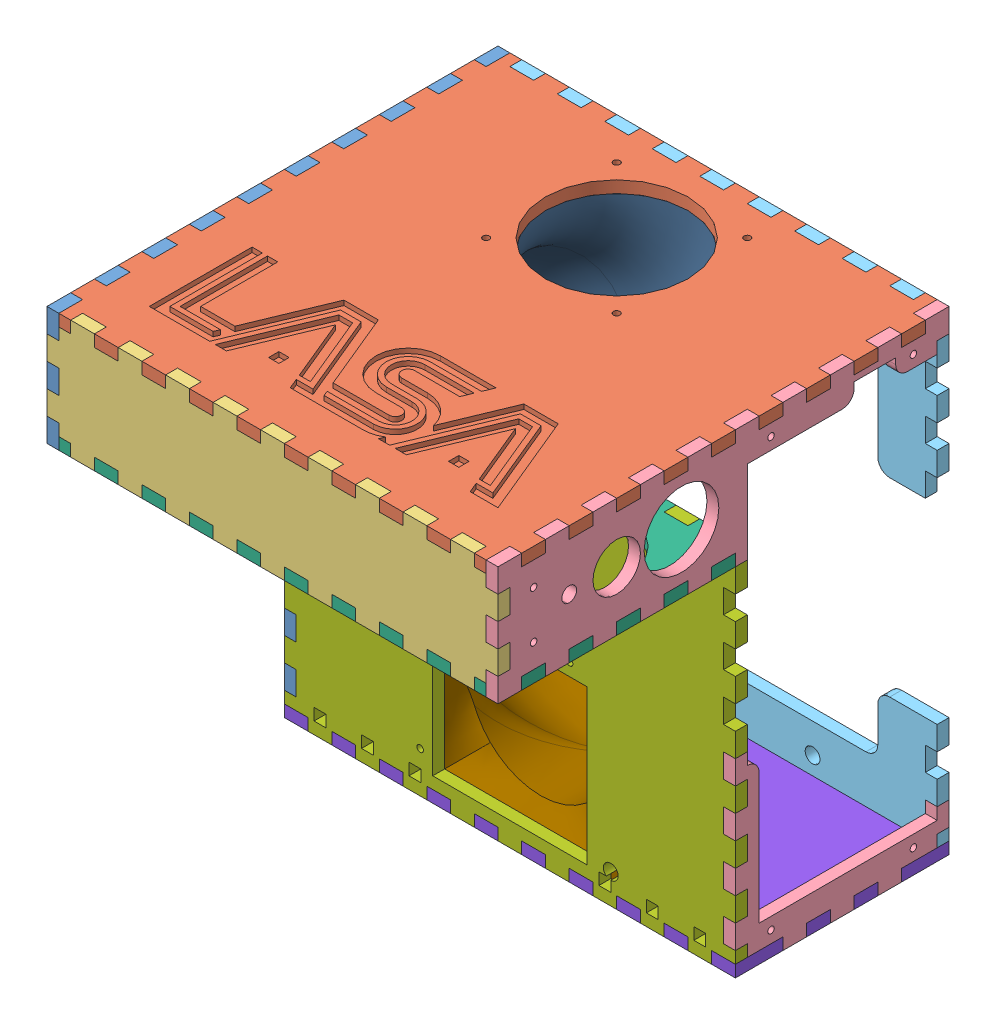
SolidWorks assembly Center Assembly, configuration Default. Lengths in mm.
Overall size (241.3 254 241.3).
10 component instances, 10 part files, 26 mates.
Components (placement in the parent):
- C Right Panel-1: C Right Panel [Default] at (96.1993 65.653 239.6839) size (6.35 254 241.3)
- C Top Panel-1: C Top Panel [Default] at (96.1993 313.303 366.6839) size (241.3 6.35 241.3)
- C Front Panel-1: C Front Panel [Default] at (96.1993 256.153 360.3339) size (241.3 63.5 6.35)
- C Left Panel-1: C Left Panel [Default] at (331.1493 65.653 239.6839) size (6.35 254 241.3)
- C Back Panel-2: C Back Panel [Default] at (96.1993 319.653 131.7339) x (1 0 0) z (0 1 0) size (241.3 6.35 254)
- C Inside Top-1: C Inside Top [Default] at (96.1993 256.153 366.6839) size (241.3 6.35 133.35)
- C Inside Back-1: C Inside Back [Default] at (96.1993 319.653 239.6839) x (1 0 0) z (0 1 0) size (241.3 6.35 196.85)
- C Bottom-1: C Bottom [Default] at (96.1993 65.653 239.6839) size (241.3 6.35 114.3)
- Ball Tube Part v2 A-1: Ball Tube Part v2 A [Default] at (261.2993 72.003 233.3339) size (177.68 162.89 99.66)
- Ball Tube Part v2 B-1: Ball Tube Part v2 B [Default] at (261.2993 200.9554 2.7815) x (1 0 0) z (0 -1 0) size (161.8 95.25 123.1)
Mates (geometry in assembly coordinates):
- Coincident1: coincident aligned: plane of C Right Panel-1 through (102.5493 319.653 366.6839) normal (0 1 0); plane of C Top Panel-1 through (96.1993 319.653 366.6839) normal (0 1 0)
- Coincident2: coincident aligned: plane of C Right Panel-1 through (96.1993 65.653 239.6839) normal (-1 0 0); plane of C Top Panel-1 through (96.1993 319.653 366.6839) normal (-1 0 0)
- Coincident3: coincident aligned: plane of C Right Panel-1 through (102.5493 256.153 366.6839) normal (0 0 1); plane of C Top Panel-1 through (96.1993 319.653 366.6839) normal (0 0 1)
- Coincident4: coincident aligned: plane of C Top Panel-1 through (96.1993 319.653 366.6839) normal (0 1 0); plane of C Front Panel-1 through (96.1993 319.653 366.6839) normal (0 1 0)
- Coincident5: coincident aligned: plane of C Right Panel-1 through (96.1993 65.653 239.6839) normal (-1 0 0); plane of C Front Panel-1 through (96.1993 256.153 366.6839) normal (-1 0 0)
- Coincident6: coincident aligned: plane of C Top Panel-1 through (96.1993 319.653 366.6839) normal (0 0 1); plane of C Front Panel-1 through (96.1993 256.153 366.6839) normal (0 0 1)
- Coincident7: coincident aligned: plane of C Front Panel-1 through (96.1993 256.153 366.6839) normal (0 0 1); plane of C Left Panel-1 through (337.4993 256.153 366.6839) normal (0 0 1)
- Coincident8: coincident aligned: plane of C Top Panel-1 through (96.1993 319.653 366.6839) normal (0 1 0); plane of C Left Panel-1 through (337.4993 319.653 366.6839) normal (0 1 0)
- Coincident9: coincident aligned: plane of C Top Panel-1 through (337.4993 319.653 366.6839) normal (1 0 0); plane of C Left Panel-1 through (337.4993 65.653 239.6839) normal (1 0 0)
- Coincident10: coincident aligned: plane of C Left Panel-1 through (337.4993 319.653 125.3839) normal (0 0 -1); plane of C Back Panel-2 through (96.1993 319.653 125.3839) normal (0 0 -1)
- Coincident11: coincident aligned: plane of C Top Panel-1 through (96.1993 319.653 366.6839) normal (0 1 0); plane of C Back Panel-2 through (96.1993 319.653 125.3839) normal (0 1 0)
- Coincident12: coincident aligned: plane of C Left Panel-1 through (337.4993 65.653 239.6839) normal (1 0 0); plane of C Back Panel-2 through (337.4993 319.653 125.3839) normal (1 0 0)
- Coincident13: coincident aligned: plane of C Front Panel-1 through (96.1993 256.153 366.6839) normal (0 0 1); plane of C Inside Top-1 through (96.1993 262.503 366.6839) normal (0 0 1)
- Coincident14: coincident aligned: plane of C Left Panel-1 through (337.4993 65.653 239.6839) normal (1 0 0); plane of C Inside Top-1 through (337.4993 262.503 366.6839) normal (1 0 0)
- Coincident15: coincident aligned: plane of C Right Panel-1 through (102.5493 256.153 239.6839) normal (0 -1 0); plane of C Inside Top-1 through (96.1993 256.153 366.6839) normal (0 -1 0)
- Coincident17: coincident aligned: plane of C Left Panel-1 through (337.4993 65.653 239.6839) normal (1 0 0); plane of C Inside Back-1 through (337.4993 319.653 233.3339) normal (1 0 0)
- Coincident18: coincident aligned: plane of C Left Panel-1 through (337.4993 65.653 125.3839) normal (0 -1 0); plane of C Inside Back-1 through (96.1993 65.653 233.3339) normal (0 -1 0)
- Coincident19: coincident aligned: plane of C Left Panel-1 through (337.4993 65.653 125.3839) normal (0 -1 0); plane of C Bottom-1 through (96.1993 65.653 239.6839) normal (0 -1 0)
- Coincident20: coincident aligned: plane of C Left Panel-1 through (337.4993 65.653 239.6839) normal (1 0 0); plane of C Bottom-1 through (337.4993 72.003 239.6839) normal (1 0 0)
- Coincident21: coincident aligned: plane of C Inside Back-1 through (96.1993 319.653 239.6839) normal (0 0 1); plane of C Bottom-1 through (96.1993 72.003 239.6839) normal (0 0 1)
- Coincident27: coincident anti-aligned: plane of C Inside Back-1 through (96.1993 319.653 233.3339) normal (0 0 -1); plane of Ball Tube Part v2 A-1 through (216.8493 119.628 233.3339) normal (0 0 1)
- Coincident28: coincident anti-aligned: plane of C Bottom-1 through (96.1993 72.003 239.6839) normal (0 1 0); plane of Ball Tube Part v2 A-1 through (159.3243 72.003 226.9839) normal (0 -1 0)
- Coincident29: coincident anti-aligned: line of C Inside Back-1 through (175.5743 78.353 233.3339) axis (0 1 0); line of Ball Tube Part v2 A-1 through (175.5743 160.903 233.3339) axis (0 -1 0)
- Coincident30: coincident anti-aligned: plane of C Top Panel-1 through (96.1993 313.303 366.6839) normal (0 -1 0); plane of Ball Tube Part v2 B-1 through (216.8493 313.303 182.5339) normal (0 1 0)
- Coincident31: coincident aligned: cylinder of C Top Panel-1 through (216.8493 313.303 182.5339) axis (0 1 0) radius 38.1; circle of Ball Tube Part v2 B-1
- Parallel5: parallel aligned: plane of C Right Panel-1 through (96.1993 65.653 239.6839) normal (-1 0 0); plane of Ball Tube Part v2 B-1 through (169.2243 306.953 230.1589) normal (-1 0 0)
